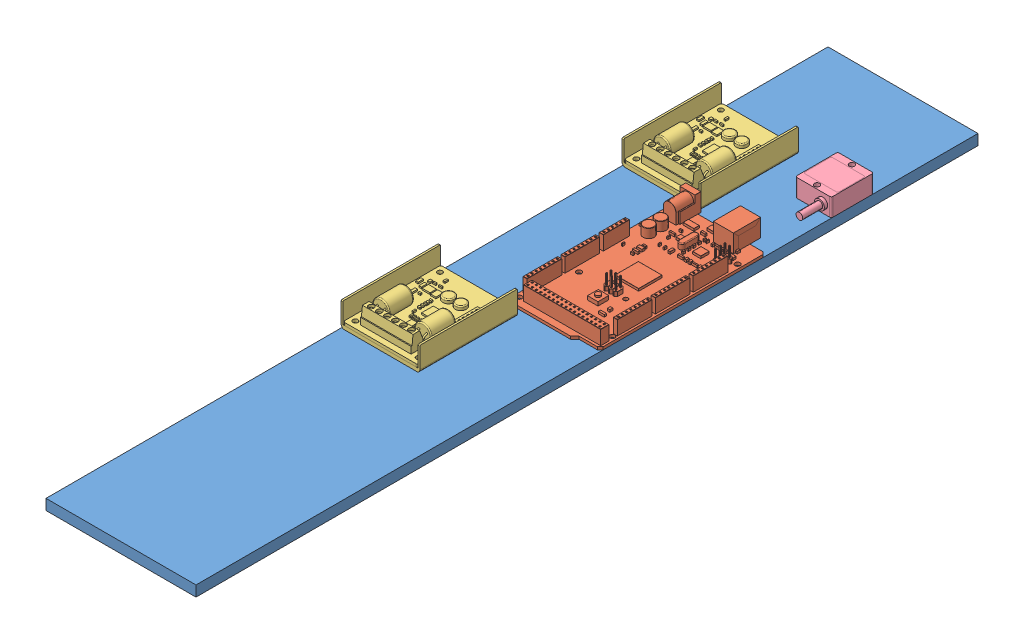
SolidWorks assembly electronics_plate, configuration Default. Lengths in mm.
Overall size (90 20.96 469.2).
5 component instances, 4 part files, 12 mates.
Components (placement in the parent):
- electronics_plate-2: electronics_plate [Default] at (117.0343 251.6082 591.6759) size (90 6.35 469.2)
- ArduinoMega-2: ArduinoMega [Default] at (180.3262 259.6092 300.8759) x (0 0 -1) z (0 -1 0) size (107.95 53.42 12.95)
- motor_controller-1: motor_controller [Default] at (140.6563 260.1796 216.7494) x (0 0 -1) z (1 0 0) size (58.55 14.61 47.24)
- motor_controller-2: motor_controller [Default] at (140.6563 260.1796 385.2964) x (0 0 -1) z (1 0 0) size (58.55 14.61 47.24)
- Accelerometer-1: Accelerometer [Default] at (196.2343 263.3582 197.7882) x (0 0 -1) z (1 0 0) size (39.4 10.8 21.6)
Mates (geometry in assembly coordinates):
- Coincident1: coincident anti-aligned: plane of electronics_plate-2 through (117.0343 257.9582 591.6759) normal (0 1 0); plane of ArduinoMega-2 through (153.6181 257.9582 250.0759) normal (0 -1 0)
- Coincident6: coincident anti-aligned: line of electronics_plate-2 through (207.0343 257.9582 591.6759) axis (0 0 -1); line of ArduinoMega-2 through (207.0343 257.9582 251.5999) axis (0 0 1)
- Distance8: distance = 240 mm: line of ArduinoMega-2 through (191.7943 257.9582 351.6759) axis (-1 0 0); line of electronics_plate-2 through (117.0343 257.9582 591.6759) axis (1 0 0)
- Coincident15: coincident anti-aligned: plane of electronics_plate-2 through (117.0343 257.9582 591.6759) normal (0 1 0); plane of motor_controller-1 through (164.2783 257.9582 143.0259) normal (0 -1 0)
- Distance7: distance = 65 mm: line of electronics_plate-2 through (207.0343 257.9582 122.4759) axis (-1 0 0); line of motor_controller-1 through (162.3733 257.9582 187.4759) axis (-1 0 0)
- Coincident17: coincident aligned: plane of electronics_plate-2 through (117.0343 257.9582 591.6759) normal (-1 0 0); plane of motor_controller-1 through (117.0343 272.5632 143.0259) normal (-1 0 0)
- Coincident18: coincident anti-aligned: plane of electronics_plate-2 through (117.0343 257.9582 591.6759) normal (0 1 0); plane of motor_controller-2 through (164.2783 257.9582 311.5729) normal (0 -1 0)
- Distance5: distance = 0 mm aligned: plane of electronics_plate-2 through (117.0343 257.9582 591.6759) normal (-1 0 0); plane of motor_controller-2 through (117.0343 272.5632 306.5729) normal (-1 0 0)
- Distance6: distance = 110 mm anti-aligned: plane of motor_controller-2 through (163.1353 261.8306 356.0229) normal (0 0 -1); plane of motor_controller-1 through (140.6563 260.1796 246.0229) normal (0 0 1)
- Distance10: distance = 0 mm: line of electronics_plate-2 through (207.0343 257.9582 591.6759) axis (0 0 -1); line of Accelerometer-1 through (207.0343 257.9582 209.4882) axis (0 0 -1)
- Coincident26: coincident anti-aligned: plane of electronics_plate-2 through (117.0343 257.9582 591.6759) normal (0 1 0); plane of Accelerometer-1 through (196.2343 257.9582 197.7882) normal (0 -1 0)
- Distance12: distance = 381.1876 mm: line of Accelerometer-1 through (186.4343 257.9582 210.4882) axis (1 0 0); line of electronics_plate-2 through (117.0343 257.9582 591.6759) axis (1 0 0)
